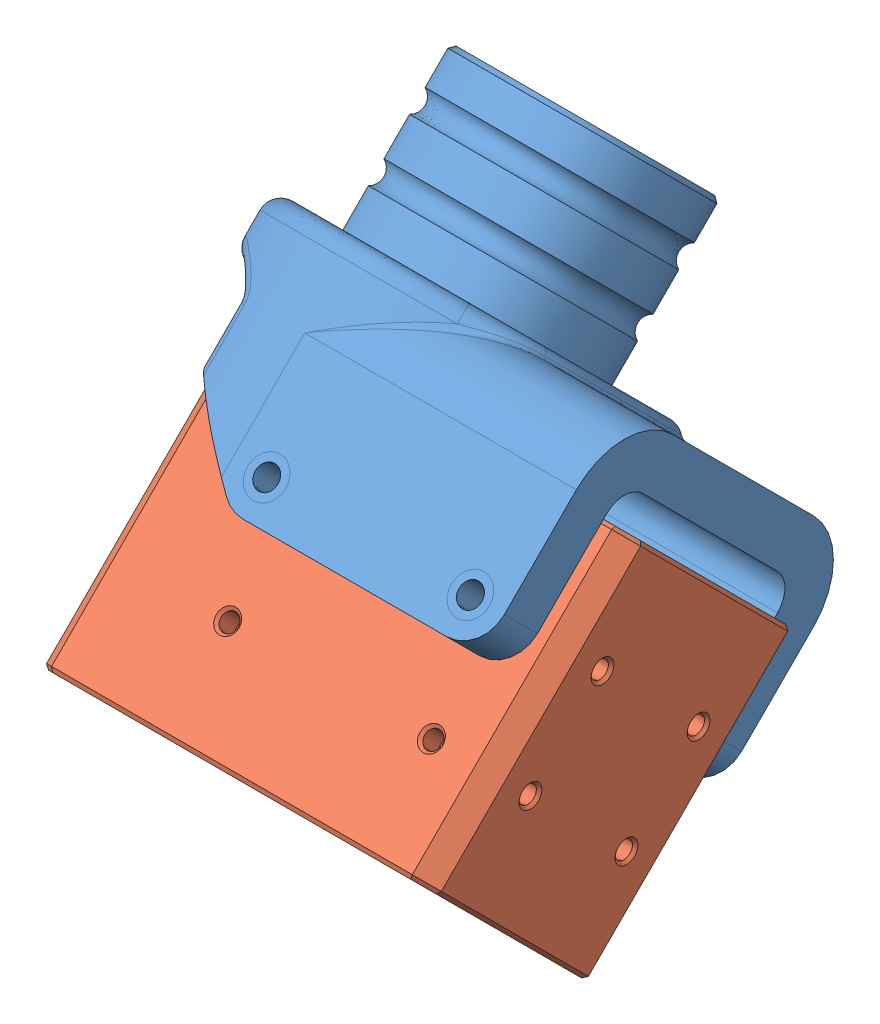
SolidWorks assembly J4 CNC Sim, configuration Default. Lengths in mm.
Overall size (55 320.38 548.3).
3 component instances, 3 part files, 3 mates.
Components (placement in the parent):
- Student_Arm_Geo-1: Student_Arm_Geo [Default] at origin size (0 320.38 548.3) (hidden)
- J4_Mount_3DP-1: J4_Mount_3DP [Default] at origin size (51.75 320.38 548.3)
- XM430-1: XM430 [Default] at (0 49.6743 303.8791) x (0 0.707107 0.707107) z (0 -0.707107 0.707107) size (28.5 46.5 34)
Mates (geometry in assembly coordinates):
- Coincident1: coincident anti-aligned: plane of J4_Mount_3DP-1 through (0 166.7004 166.7004) normal (0 0.707107 0.707107); plane of XM430-1 through (-11.25 51.6188 281.7821) normal (0 -0.707107 -0.707107)
- Concentric1: concentric aligned: cylinder of J4_Mount_3DP-1 through (4 67.8823 313.6019) axis (0 0.707107 0.707107) radius 1.35; cylinder of XM430-1 through (4 61.3085 307.0281) axis (0 0.707107 0.707107) radius 1.025
- Concentric2: concentric aligned: cylinder of J4_Mount_3DP-1 through (28 67.8823 313.6019) axis (0 0.707107 0.707107) radius 1.35; cylinder of XM430-1 through (28 61.3085 307.0281) axis (0 0.707107 0.707107) radius 1.025
